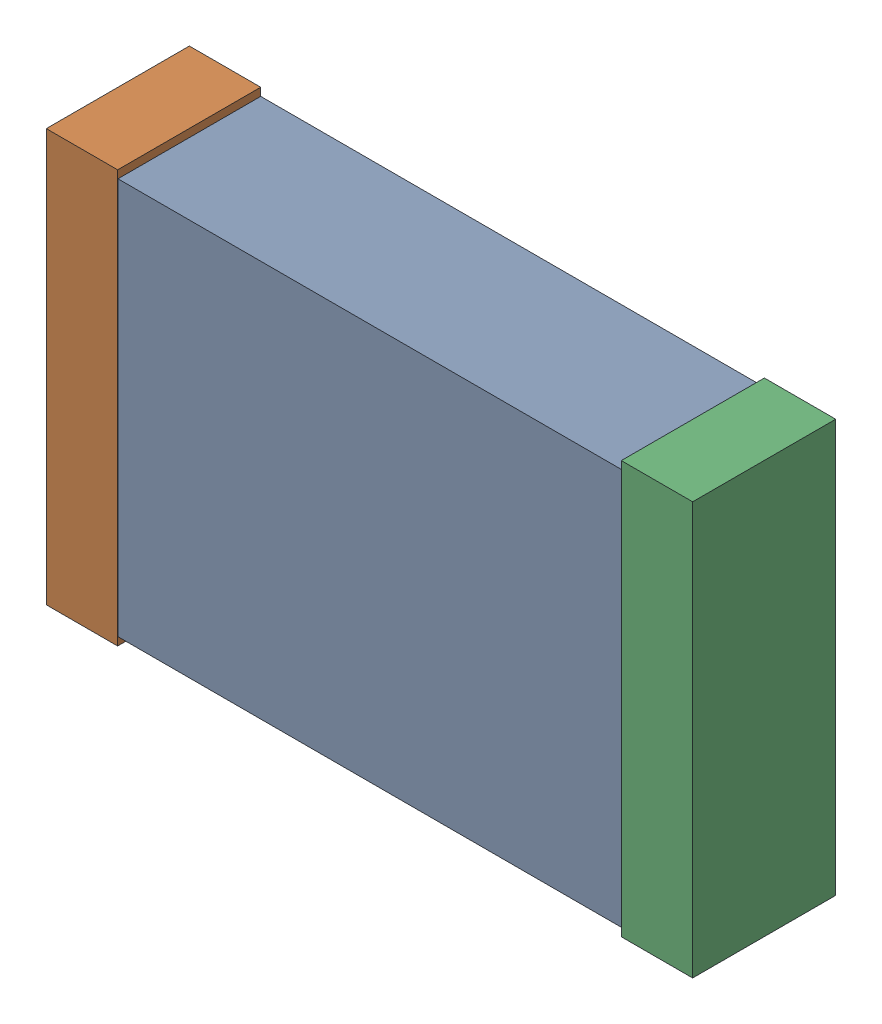
SolidWorks assembly C2, configuration Default. Lengths in mm.
Overall size (2.04 1.3 0.45).
6 component instances, 2 part files, 0 mates.
Components (placement in the parent):
- 870943200-1: 870943200 [Default] at (73.3798 2.4108 0) size (2 1.25 0.45)
  - Extruded_39-1: Extruded_39 [Default] at origin size (2 1.25 0.45)
- 870943360-1: 870943360 [Default] at (72.4673 2.4108 0) size (0.23 1.3 0.45)
  - Extruded_40-1: Extruded_40 [Default] at origin size (0.23 1.3 0.45)
- 870943360-2: 870943360 [Default] at (74.2798 2.4108 0) size (0.23 1.3 0.45)
  - Extruded_40-1: Extruded_40 [Default] at origin size (0.23 1.3 0.45)
